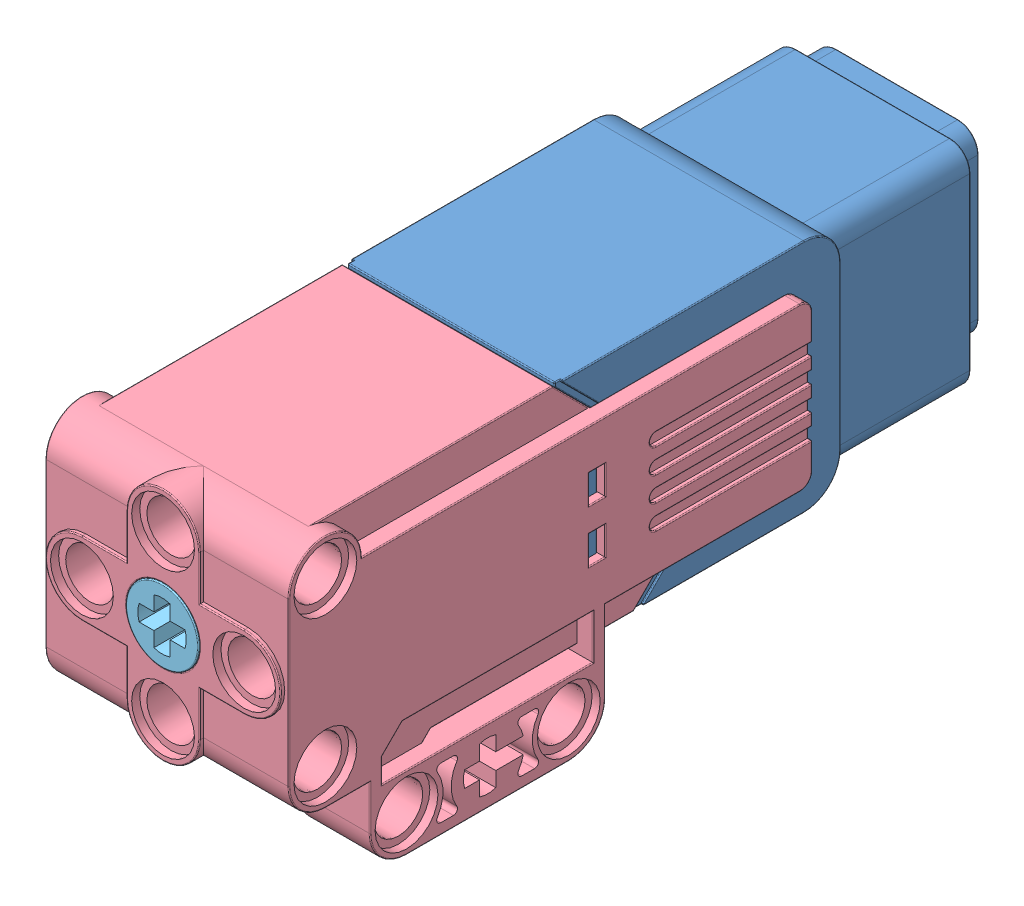
SolidWorks assembly CenterAssem, configuration Default. Lengths in mm.
Overall size (24 31.22 72.5).
8 component instances, 5 part files, 0 mates.
Components (placement in the parent):
- LEGOEV3MEDIUMMOTOR-1: LEGOEV3MEDIUMMOTOR [Default] at (35.9668 49.2307 43.2088) size (24 31.22 72.5)
  - 99455.stp-1: 99455.stp [Default] at origin size (24 31.22 72.5)
    - 99535c01.stp-1: 99535c01.stp [Default] at origin size (24 31.22 72.4)
      - 99534-White.stp-1: 99534-White.stp [Default] at origin size (22.4 23.2 44.8)
      - 54732b-LtBluishGray.stp-1: 54732b-LtBluishGray.stp [Default] at (0 0.8 -16) x (-1 0 0) z (0 0 -1) size (12 14.56 14.4)
      - 99542-MilkyWhite.stp-1: 99542-MilkyWhite.stp [Default] at (0 0 48.4) x (1 0 0) z (0 0 -1) size (20.8 20.8 2.4)
      - 99535-LtBluishGray.stp-1: 99535-LtBluishGray.stp [Default] at (0 0 28.4) size (24 31.22 52)
    - 99543-Red.stp-1: 99543-Red.stp [Default] at (0 0 47.7) size (16 16 12.4)
